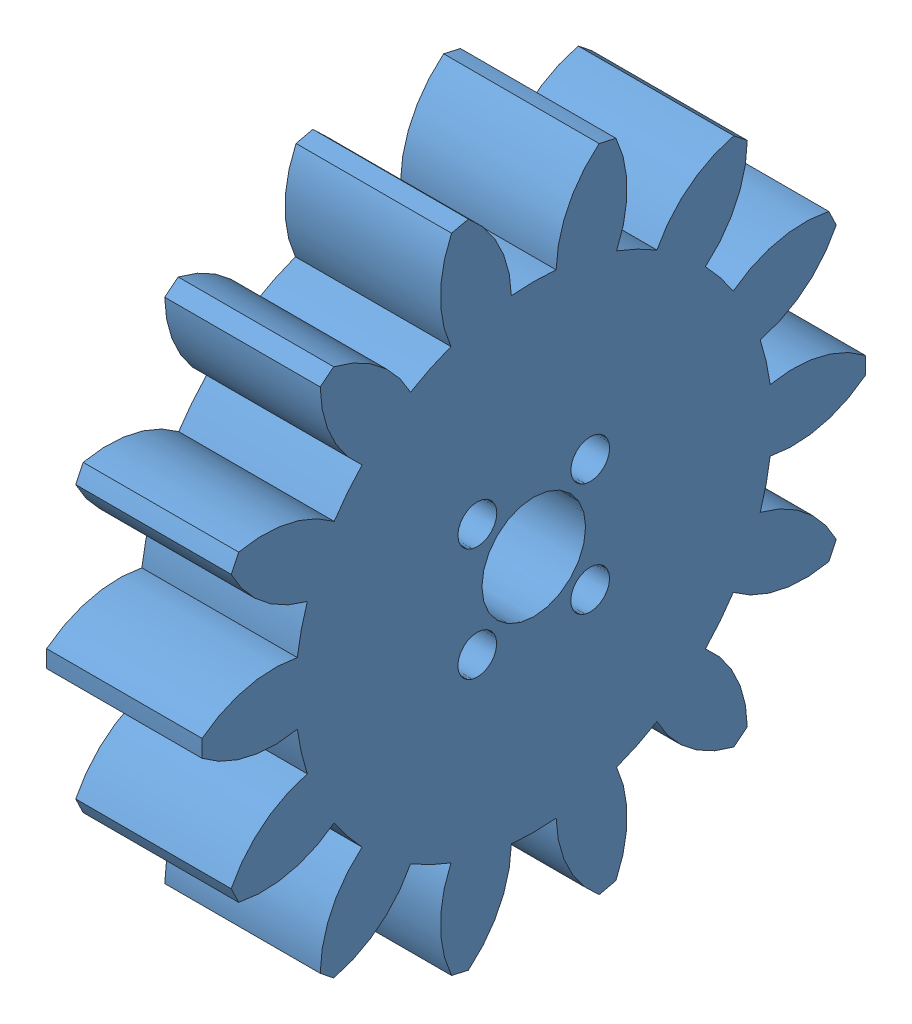
SolidWorks assembly ARMUS-103-500, configuration Défaut. Lengths in mm.
Overall size (28.58 79.69 81.28).
2 component instances, 2 part files, 4 mates.
Components (placement in the parent):
- ARMUS-REV4-501-1: ARMUS-REV4-501 [Défaut] at origin size (19.05 79.69 81.28)
- bore_set_screw_D_hub-1: bore_set_screw_D_hub [Défaut] at (-20.7023 -52.5937 -16.7801) x (0 -1 0.000796) z (0 0.000796 1) size (20.57 9.61 20.57)
Mates (geometry in assembly coordinates):
- Coincident1: coordinate: point of ARMUS-REV2-X01-1
- Concentric1: concentric anti-aligned: cylinder of ARMUS-REV2-X01-1 through (0 -6.91 6.921) axis (1 0 0) radius 2.3813; cylinder of bore_set_screw_D_hub-1 through (0 -6.91 6.921) axis (-1 0 0) radius 3.3722
- Concentric3: concentric anti-aligned: cylinder of ARMUS-REV2-X01-1 through (50.8001 0 0) axis (-1 0 0) radius 6.35; cylinder of bore_set_screw_D_hub-1 through (0 -0.0007 0.0007) axis (1 0 0) radius 3.175
- Coincident2: coincident anti-aligned: plane of ARMUS-REV2-X01-1 through (0 0 0) normal (-1 0 0); plane of bore_set_screw_D_hub-1 through (0 3.4539 -3.4594) normal (1 0 0)
